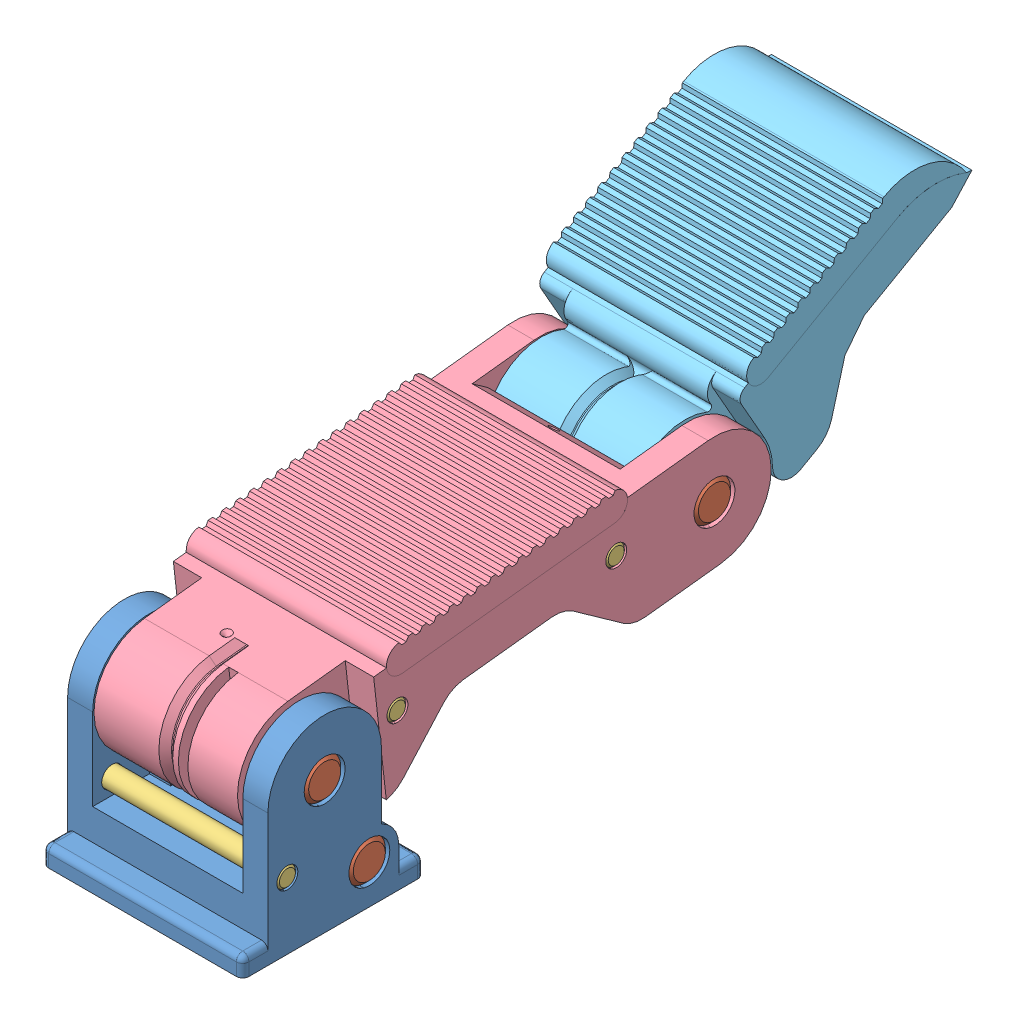
SolidWorks assembly block_finger_pp_t42, configuration Default. Lengths in mm.
Overall size (32.23 61.41 122.56).
15 component instances, 7 part files, 28 mates.
Components (placement in the parent):
- c1_t42-1: c1_t42 [Default] at origin size (31.75 29.94 28.75)
- 98381A544 D1-4 L5-4-1: 98381A544 D1-4 L5-4 [98381A544] at (0 20.9353 -30) size (31.75 6.35 6.35)
- 98381A544 D1-4 L5-4-2: 98381A544 D1-4 L5-4 [98381A544] at (0 6.175 -37.075) size (31.75 6.35 6.35)
- 98381A477 D1-8 L5-4-1: 98381A477 D1-8 L5-4 [98381A477] at (0 10.5228 -24.0875) size (31.75 3.17 3.17)
- finger_pp_t42_A-1: finger_pp_t42_A [Default] at (-0.325 20.9353 -30) x (1 0 0) z (0 -0.111473 0.993768) size (31.75 20.25 80.5)
- finger_pp_t42_B-1: finger_pp_t42_B [Default] at (-0.475 27.9023 -92.1105) x (1 0 0) z (0 -0.494638 0.869099) size (31.75 22.88 57.08)
- 98381A544 D1-4 L5-4-3: 98381A544 D1-4 L5-4 [98381A544] at (-0.325 27.9023 -92.1105) size (31.75 6.35 6.35)
- 98381A477 D1-8 L5-4-2: 98381A477 D1-8 L5-4 [98381A477] at (-0.325 24.4415 -41.8581) size (31.75 3.17 3.17)
- 98381A477 D1-8 L5-4-3: 98381A477 D1-8 L5-4 [98381A477] at (-0.325 28.3322 -76.5436) size (31.75 3.17 3.17)
- 93365A120 4-40 insert-1: 93365A120 4-40 insert [93365A120] at (-0.475 39.5312 -114.477) x (1 0 0) z (0 0.789576 -0.613653) size (4.37 3.82 4.37)
- 93365A120 4-40 insert-2: 93365A120 4-40 insert [93365A120] at (-0.475 22.7501 -101.253) x (-0.837169 0.270539 -0.475349) z (-0.546944 -0.414095 0.727583) size (4.37 3.82 4.37)
- 93365A120 4-40 insert-3: 93365A120 4-40 insert [93365A120] at (-0.325 17.6765 -81.6854) x (-0.837169 0.060969 -0.543535) z (-0.546944 -0.093321 0.831951) size (4.37 3.82 4.37)
- 91253A106 4-40 L1-4 countersunk-1: 91253A106 4-40 L1-4 countersunk [91253A106] at (-0.475 38.2295 -116.1519) x (1 0 0) z (0 -0.613653 -0.789576) size (6.48 6.48 6.63)
- 91253A106 4-40 L1-4 countersunk-2: 91253A106 4-40 L1-4 countersunk [91253A106] at (-0.475 20.9066 -102.3022) x (1 0 0) z (0 -0.869099 -0.494638) size (6.48 6.48 6.63)
- 91253A106 4-40 L1-4 countersunk-3: 91253A106 4-40 L1-4 countersunk [91253A106] at (-0.325 15.5685 -81.9219) x (1 0 0) z (0 -0.993768 -0.111473) size (6.48 6.48 6.63)
Mates (geometry in assembly coordinates):
- Concentric1: concentric aligned: cylinder of c1_t42-1 through (-15.875 20.9353 -30) axis (1 0 0) radius 3.25; cylinder of 98381A544 D1-4 L5-4-1 through (-15.875 20.9353 -30) axis (1 0 0) radius 3.175
- Coincident1: coincident aligned: plane of c1_t42-1 through (15.875 20.9353 -30) normal (1 0 0); plane of 98381A544 D1-4 L5-4-1 through (15.875 20.9353 -30) normal (1 0 0)
- Concentric2: concentric aligned: cylinder of c1_t42-1 through (-15.875 6.175 -37.075) axis (1 0 0) radius 3.25; cylinder of 98381A544 D1-4 L5-4-2 through (-15.875 6.175 -37.075) axis (1 0 0) radius 3.175
- Coincident2: coincident aligned: plane of c1_t42-1 through (15.875 20.9353 -30) normal (1 0 0); plane of 98381A544 D1-4 L5-4-2 through (15.875 6.175 -37.075) normal (1 0 0)
- Concentric3: concentric aligned: cylinder of c1_t42-1 through (-15.875 10.5228 -24.0875) axis (1 0 0) radius 1.6625; cylinder of 98381A477 D1-8 L5-4-1 through (-15.875 10.5228 -24.0875) axis (1 0 0) radius 1.5875
- Coincident3: coincident aligned: plane of c1_t42-1 through (15.875 20.9353 -30) normal (1 0 0); plane of 98381A477 D1-8 L5-4-1 through (15.875 10.5228 -24.0875) normal (1 0 0)
- Concentric4: concentric aligned: cylinder of 98381A544 D1-4 L5-4-1 through (-15.875 20.9353 -30) axis (1 0 0) radius 3.175; cylinder of finger_pp_t42_A-1 through (-16.2 20.9353 -30) axis (1 0 0) radius 3.525
- Distance1: distance = 0.2 mm anti-aligned: plane of c1_t42-1 through (-11.9 20.9353 -30) normal (1 0 0); plane of finger_pp_t42_A-1 through (-11.7 13.0113 -40.0962) normal (-1 0 0)
- Concentric5: concentric aligned: cylinder of finger_pp_t42_A-1 through (-16.2 27.9023 -92.1105) axis (1 0 0) radius 3.25; cylinder of 98381A544 D1-4 L5-4-3 through (-16.2 27.9023 -92.1105) axis (1 0 0) radius 3.175
- Coincident5: coincident aligned: plane of finger_pp_t42_A-1 through (15.55 20.9353 -30) normal (1 0 0); plane of 98381A544 D1-4 L5-4-3 through (15.55 27.9023 -92.1105) normal (1 0 0)
- Concentric6: concentric aligned: cylinder of finger_pp_t42_B-1 through (-16.35 27.9023 -92.1105) axis (1 0 0) radius 3.525; cylinder of 98381A544 D1-4 L5-4-3 through (-16.2 27.9023 -92.1105) axis (1 0 0) radius 3.175
- Distance2: distance = 0.2 mm anti-aligned: plane of finger_pp_t42_A-1 through (-12.05 27.9023 -92.1105) normal (1 0 0); plane of finger_pp_t42_B-1 through (-11.85 27.9023 -92.1105) normal (-1 0 0)
- Concentric7: concentric aligned: cylinder of finger_pp_t42_A-1 through (-16.2 24.4415 -41.8581) axis (1 0 0) radius 1.6625; cylinder of 98381A477 D1-8 L5-4-2 through (-16.2 24.4415 -41.8581) axis (1 0 0) radius 1.5875
- Coincident7: coincident aligned: plane of finger_pp_t42_A-1 through (15.55 20.9353 -30) normal (1 0 0); plane of 98381A477 D1-8 L5-4-2 through (15.55 24.4415 -41.8581) normal (1 0 0)
- Concentric8: concentric aligned: cylinder of finger_pp_t42_A-1 through (-16.2 28.3322 -76.5436) axis (1 0 0) radius 1.6625; cylinder of 98381A477 D1-8 L5-4-3 through (-16.2 28.3322 -76.5436) axis (1 0 0) radius 1.5875
- Coincident8: coincident aligned: plane of finger_pp_t42_A-1 through (15.55 20.9353 -30) normal (1 0 0); plane of 98381A477 D1-8 L5-4-3 through (15.55 28.3322 -76.5436) normal (1 0 0)
- Concentric9: concentric aligned: cylinder of finger_pp_t42_A-1 through (-0.325 22.1484 -81.1838) axis (0 -0.993768 -0.111473) radius 1.85; circle of 93365A120 4-40 insert-3
- Coincident9: coincident aligned: plane of finger_pp_t42_A-1 through (15.55 11.9914 -31.0033) normal (0 -0.993768 -0.111473); plane of 93365A120 4-40 insert-3 through (-0.325 17.6765 -81.6854) normal (0 -0.993768 -0.111473)
- Concentric10: concentric aligned: cylinder of finger_pp_t42_B-1 through (-0.475 26.2265 -99.2744) axis (0 -0.869099 -0.494638) radius 1.85; circle of 93365A120 4-40 insert-2
- Coincident10: coincident aligned: plane of finger_pp_t42_B-1 through (15.4 20.0804 -96.5622) normal (0 -0.869099 -0.494638); plane of 93365A120 4-40 insert-2 through (-0.475 22.7501 -101.253) normal (0 -0.869099 -0.494638)
- Concentric11: concentric aligned: cylinder of finger_pp_t42_B-1 through (-0.475 42.2926 -110.9239) axis (0 -0.613653 -0.789576) radius 1.85; circle of 93365A120 4-40 insert-1
- Coincident11: coincident aligned: plane of finger_pp_t42_B-1 through (-21.35 41.5051 -116.0112) normal (0 -0.613653 -0.789576); plane of 93365A120 4-40 insert-1 through (-0.475 39.5312 -114.477) normal (0 -0.613653 -0.789576)
- Concentric12: concentric anti-aligned: circle of 93365A120 4-40 insert-1; circle of 91253A106 4-40 L1-4 countersunk-1
- Coincident12: coincident: circle of 93365A120 4-40 insert-1; cone of 91253A106 4-40 L1-4 countersunk-1 through (-0.475 39.5232 -114.4873) axis (0 0.613653 0.789576)
- Concentric13: concentric anti-aligned: circle of 93365A120 4-40 insert-2; circle of 91253A106 4-40 L1-4 countersunk-2
- Coincident13: coincident: circle of 93365A120 4-40 insert-2; cone of 91253A106 4-40 L1-4 countersunk-2 through (-0.475 22.7388 -101.2594) axis (0 0.869099 0.494638)
- Concentric14: concentric anti-aligned: circle of 93365A120 4-40 insert-3; circle of 91253A106 4-40 L1-4 countersunk-3
- Coincident14: coincident: circle of 93365A120 4-40 insert-3; cone of 91253A106 4-40 L1-4 countersunk-3 through (-0.325 17.6636 -81.6868) axis (0 0.993768 0.111473)
